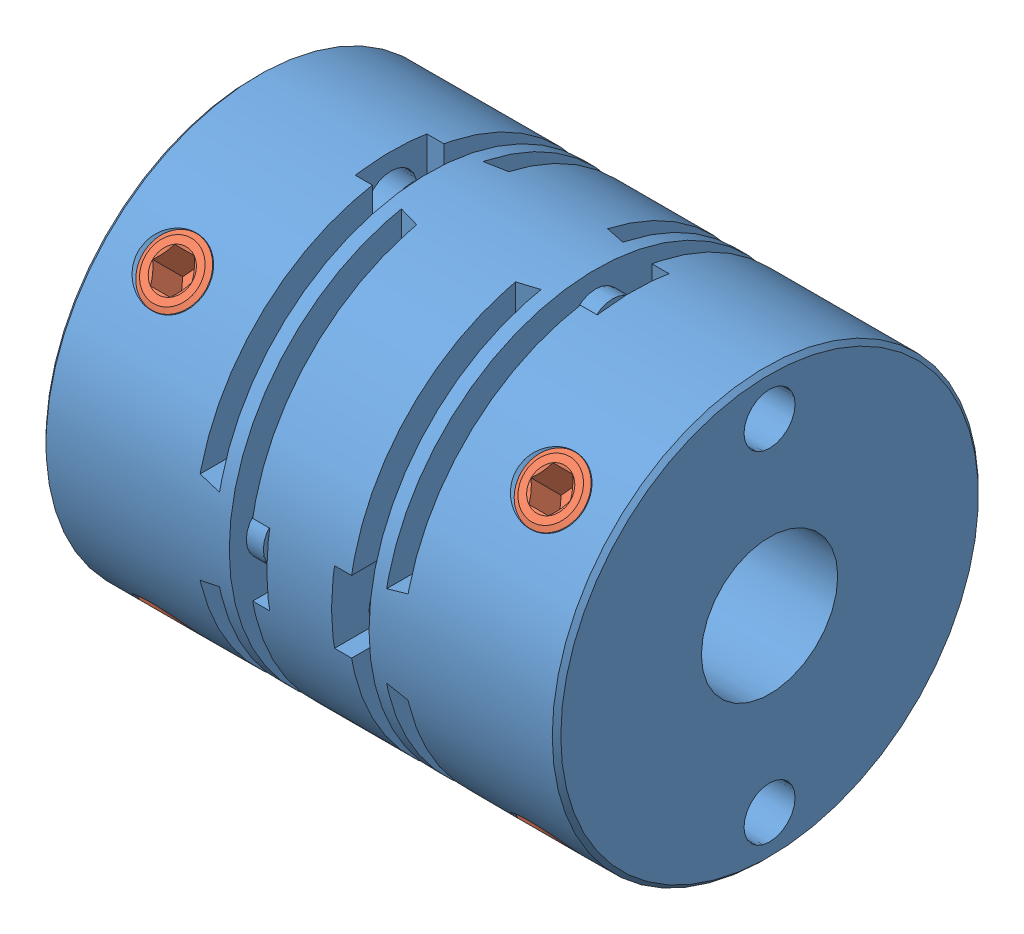
SolidWorks assembly MCGL25_8_8, configuration 默认. Lengths in mm.
Overall size (30.2 25 25).
5 component instances, 2 part files, 4 mates.
Components (placement in the parent):
- MCGL25_8_8_p-1: MCGL25_8_8_p [默认] at origin size (30.2 25 25)
- Headless_pin_DIN_913___M4x6-1: Headless_pin_DIN_913___M4x6 [默认] at (4 -8.8388 8.8388) x (0 0.707107 -0.707107) z (-1 0 0) size (6.1 4 4)
- Headless_pin_DIN_913___M4x6-2: Headless_pin_DIN_913___M4x6 [默认] at (26.2 -8.8388 8.8388) x (0 0.707107 -0.707107) z (-1 0 0) size (6.1 4 4)
- Headless_pin_DIN_913___M4x6-3: Headless_pin_DIN_913___M4x6 [默认] at (4 8.8388 8.8388) x (0 -0.707107 -0.707107) z (-1 0 0) size (6.1 4 4)
- Headless_pin_DIN_913___M4x6-4: Headless_pin_DIN_913___M4x6 [默认] at (26.2 8.8388 8.8388) x (0 -0.707107 -0.707107) z (-1 0 0) size (6.1 4 4)
Mates (geometry in assembly coordinates):
- 重合1: coincident anti-aligned: line of MCGL25_8_8_p-1 through (4 -50 50) axis (0 0.707107 -0.707107); line of Headless_pin_DIN_913___M4x6-1 through (4 48.3661 -48.3661) axis (0 -0.707107 0.707107)
- 重合2: coincident anti-aligned: line of MCGL25_8_8_p-1 through (26.2 -50 50) axis (0 0.707107 -0.707107); line of Headless_pin_DIN_913___M4x6-2 through (26.2 48.3661 -48.3661) axis (0 -0.707107 0.707107)
- 重合3: coincident anti-aligned: line of MCGL25_8_8_p-1 through (4 50 50) axis (0 -0.707107 -0.707107); line of Headless_pin_DIN_913___M4x6-3 through (4 -48.3661 -48.3661) axis (0 0.707107 0.707107)
- 重合4: coincident anti-aligned: line of MCGL25_8_8_p-1 through (26.2 50 50) axis (0 -0.707107 -0.707107); line of Headless_pin_DIN_913___M4x6-4 through (26.2 -48.3661 -48.3661) axis (0 0.707107 0.707107)
